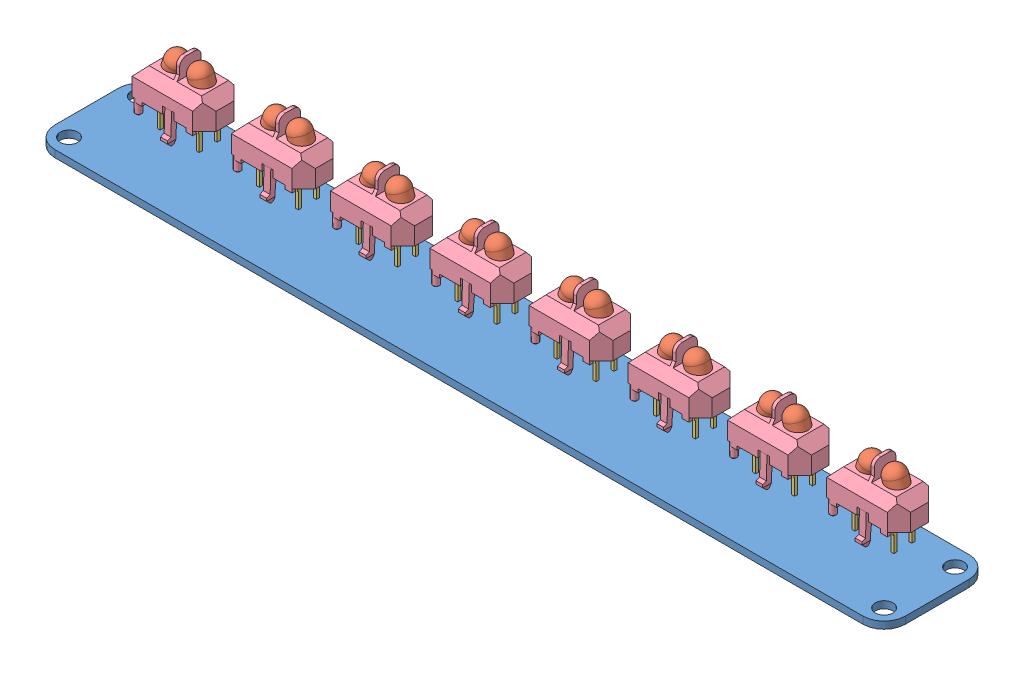
SolidWorks assembly ir sensor array, configuration Default. Lengths in mm.
Overall size (120 11.02 15).
33 component instances, 4 part files, 10 mates.
Components (placement in the parent):
- PCB-1: PCB [Default] at (36.6111 62.8298 95.9471) size (120 1 15)
- TCRT5000.stp-1: TCRT5000.stp [Default] at (-12.7889 66.8297 92.1471) x (0 0 -1) z (1 0 0) size (7 10.52 10.2)
  - LEDs.stp-1: LEDs.stp [Default] at origin size (2.8 2.98 6.71)
  - Metal Contacts.stp-1: Metal Contacts.stp [Default] at origin size (3.19 4.01 5.9)
  - TCRT5000 v1.stp-1: TCRT5000 v1.stp [Default] at origin size (7 10.02 10.2)
- TCRT5000.stp-2: TCRT5000.stp [Default] at (1.2111 66.8297 92.1471) x (0 0 -1) z (1 0 0) size (7 10.52 10.2)
  - LEDs.stp-1: LEDs.stp [Default] at origin size (2.8 2.98 6.71)
  - Metal Contacts.stp-1: Metal Contacts.stp [Default] at origin size (3.19 4.01 5.9)
  - TCRT5000 v1.stp-1: TCRT5000 v1.stp [Default] at origin size (7 10.02 10.2)
- TCRT5000.stp-3: TCRT5000.stp [Default] at (15.2111 66.8297 92.1471) x (0 0 -1) z (1 0 0) size (7 10.52 10.2)
  - LEDs.stp-1: LEDs.stp [Default] at origin size (2.8 2.98 6.71)
  - Metal Contacts.stp-1: Metal Contacts.stp [Default] at origin size (3.19 4.01 5.9)
  - TCRT5000 v1.stp-1: TCRT5000 v1.stp [Default] at origin size (7 10.02 10.2)
- TCRT5000.stp-4: TCRT5000.stp [Default] at (29.2111 66.8297 92.1471) x (0 0 -1) z (1 0 0) size (7 10.52 10.2)
  - LEDs.stp-1: LEDs.stp [Default] at origin size (2.8 2.98 6.71)
  - Metal Contacts.stp-1: Metal Contacts.stp [Default] at origin size (3.19 4.01 5.9)
  - TCRT5000 v1.stp-1: TCRT5000 v1.stp [Default] at origin size (7 10.02 10.2)
- TCRT5000.stp-5: TCRT5000.stp [Default] at (43.2111 66.8297 92.1471) x (0 0 -1) z (1 0 0) size (7 10.52 10.2)
  - LEDs.stp-1: LEDs.stp [Default] at origin size (2.8 2.98 6.71)
  - Metal Contacts.stp-1: Metal Contacts.stp [Default] at origin size (3.19 4.01 5.9)
  - TCRT5000 v1.stp-1: TCRT5000 v1.stp [Default] at origin size (7 10.02 10.2)
- TCRT5000.stp-6: TCRT5000.stp [Default] at (57.2111 66.8297 92.1471) x (0 0 -1) z (1 0 0) size (7 10.52 10.2)
  - LEDs.stp-1: LEDs.stp [Default] at origin size (2.8 2.98 6.71)
  - Metal Contacts.stp-1: Metal Contacts.stp [Default] at origin size (3.19 4.01 5.9)
  - TCRT5000 v1.stp-1: TCRT5000 v1.stp [Default] at origin size (7 10.02 10.2)
- TCRT5000.stp-7: TCRT5000.stp [Default] at (71.2111 66.8297 92.1471) x (0 0 -1) z (1 0 0) size (7 10.52 10.2)
  - LEDs.stp-1: LEDs.stp [Default] at origin size (2.8 2.98 6.71)
  - Metal Contacts.stp-1: Metal Contacts.stp [Default] at origin size (3.19 4.01 5.9)
  - TCRT5000 v1.stp-1: TCRT5000 v1.stp [Default] at origin size (7 10.02 10.2)
- TCRT5000.stp-8: TCRT5000.stp [Default] at (85.2111 66.8297 92.1471) x (0 0 -1) z (1 0 0) size (7 10.52 10.2)
  - LEDs.stp-1: LEDs.stp [Default] at origin size (2.8 2.98 6.71)
  - Metal Contacts.stp-1: Metal Contacts.stp [Default] at origin size (3.19 4.01 5.9)
  - TCRT5000 v1.stp-1: TCRT5000 v1.stp [Default] at origin size (7 10.02 10.2)
Mates (geometry in assembly coordinates):
- Distance1: distance = 0.75 mm anti-aligned: plane of IR-1 through (-15.3889 64.5798 91.9471) normal (0 -1 0); plane of PCB-1 through (36.6111 63.8298 95.9471) normal (0 1 0)
- Parallel1: parallel anti-aligned: plane of PCB-1 through (36.6111 63.8298 95.9471) normal (0 1 0); plane of IR-1 through (-15.3889 64.5798 91.9471) normal (0 -1 0)
- Distance2: distance = 3.5 mm: cylinder of IR-1 through (-15.3889 65.8298 91.9471) axis (0 -1 0) radius 2.75; plane of PCB-1 through (-23.3889 63.8298 88.4471) normal (0 0 -1)
- Distance3: distance = 8 mm: cylinder of IR-1 through (-15.3889 65.8298 91.9471) axis (0 -1 0) radius 2.75; plane of PCB-1 through (-23.3889 63.8298 88.4471) normal (-1 0 0)
- Distance4: distance = 0.75 mm anti-aligned: plane of IR-2 through (-9.3889 64.5798 91.9471) normal (0 -1 0); plane of PCB-1 through (36.6111 63.8298 95.9471) normal (0 1 0)
- Distance5: distance = 3.5 mm: cylinder of IR-2 through (-9.3889 65.8298 91.9471) axis (0 -1 0) radius 2.75; plane of PCB-1 through (-23.3889 63.8298 88.4471) normal (0 0 -1)
- Distance6: distance = 6 mm: cylinder of IR-2 through (-9.3889 65.8298 91.9471) axis (0 -1 0) radius 2.75; cylinder of IR-1 through (-15.3889 65.8298 91.9471) axis (0 -1 0) radius 2.75
- Tangent4: tangent anti-aligned: plane of PCB-1 through (36.6111 63.8298 95.9471) normal (0 1 0); cylinder of TCRT5000.stp-1/TCRT5000 v1.stp-1 through (-12.7889 64.0903 94.7076) axis (1 0 0) radius 0.2605
- Distance8: distance = 0.8 mm aligned: plane of TCRT5000.stp-1/TCRT5000 v1.stp-1 through (-12.7889 69.0809 89.2471) normal (0 0 -1); plane of PCB-1 through (-23.3889 63.8298 88.4471) normal (0 0 -1)
- Distance9: distance = 5.5 mm aligned: plane of TCRT5000.stp-1/TCRT5000 v1.stp-1 through (-17.8889 66.8297 92.1471) normal (-1 0 0); plane of PCB-1 through (-23.3889 63.8298 88.4471) normal (-1 0 0)
